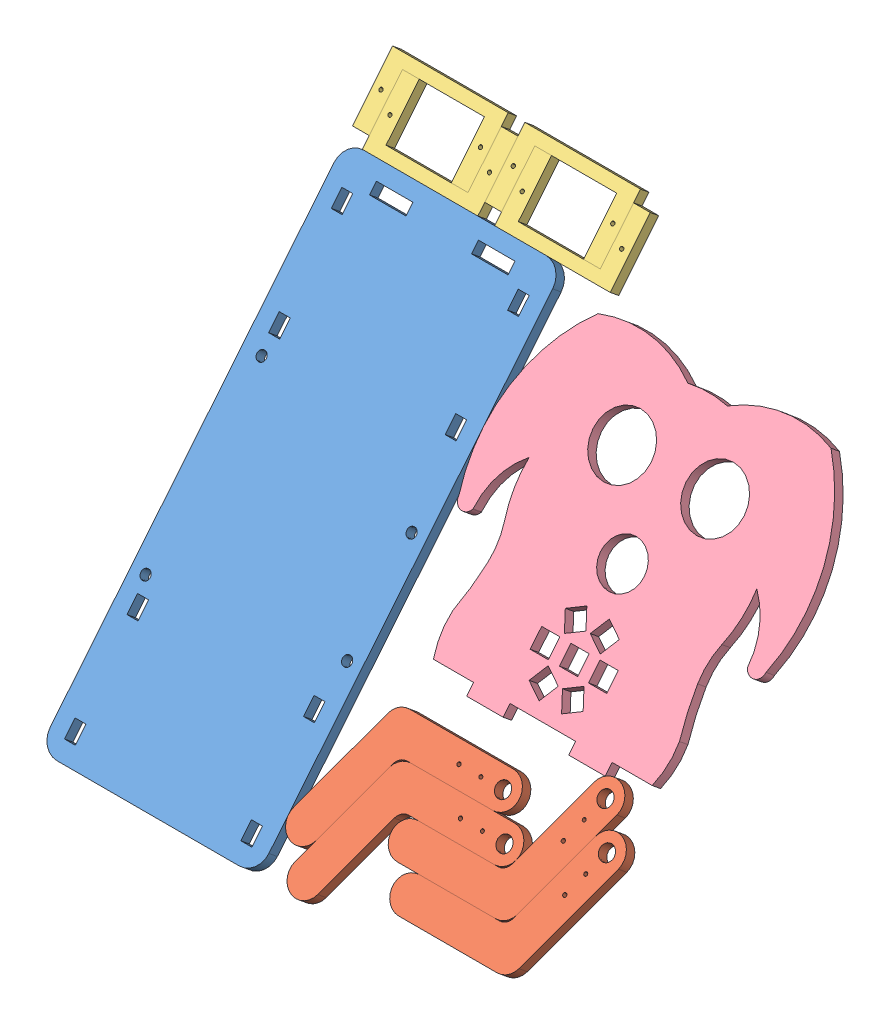
SolidWorks assembly nelo_laser_cutting, configuration Default. Lengths in mm.
Overall size (150 131.69 110.02).
10 component instances, 4 part files, 31 mates.
Components (placement in the parent):
- Base-1: Base [Default] at (2.0044 259.9739 585.3012) x (1 0 0) z (0 -0.774097 0.633066) size (60 3 133)
- leg-1: leg [Default] at (79.2182 266.4842 583.8525) x (0.369302 0.719376 -0.588315) z (-0.929309 0.285876 -0.233793) size (46.53 3 35.49)
- leg-2: leg [Default] at (117.2177 253.7498 590.3913) x (1 0 0) z (0 -0.774097 0.633066) size (46.53 3 35.49)
- leg-3: leg [Default] at (85.3263 259.5173 589.5501) x (0.369302 0.719376 -0.588315) z (-0.929309 0.285876 -0.233793) size (46.53 3 35.49)
- leg-4: leg [Default] at (111.1097 260.7167 584.6937) x (1 0 0) z (0 -0.774097 0.633066) size (46.53 3 35.49)
- servo_support-5: servo_support [Default] at (38.3044 357.0457 505.9147) x (-1 0 0) z (0 0.633066 0.774097) size (31.7 17.4 3)
- servo_support-6: servo_support [Default] at (2.0044 345.8987 515.0308) x (1 0 0) z (0 0.633066 0.774097) size (31.7 17.4 3)
- servo_support-7: servo_support [Default] at (38.3044 345.8987 515.0308) x (1 0 0) z (0 0.633066 0.774097) size (31.7 17.4 3)
- servo_support-8: servo_support [Default] at (42.9044 358.9449 508.237) x (1 0 0) z (0 -0.633066 -0.774097) size (31.7 17.4 3)
- dog_face-1: dog_face [Default] at (65.0617 342.7 517.6468) x (0 -0.774097 0.633066) z (0 0.633066 0.774097) size (79.03 88.48 3)
Mates (geometry in assembly coordinates):
- Coincident2: coincident: plane of Base-1 through (57.0044 246.3911 600.2848) normal (0 0.633066 0.774097); plane of leg-4 through (127.7168 278.9626 573.6475) normal (0 0.633066 0.774097)
- Coincident4: coincident: plane of leg-2 through (133.8248 271.9957 579.3451) normal (0 0.633066 0.774097); plane of leg-4 through (127.7168 278.9626 573.6475) normal (0 0.633066 0.774097)
- Coincident10: coincident: plane of leg-2 through (118.2097 254.9769 593.2633) normal (0 0.774097 -0.633066); plane of leg-4 through (90.1917 254.9769 593.2633) normal (0 -0.774097 0.633066)
- Coincident11: coincident: plane of leg-2 through (129.6429 273.2821 578.293) normal (-0.929309 0.285876 -0.233793); plane of leg-4 through (131.8987 277.6761 574.6996) normal (0.929309 -0.285876 0.233793)
- Coincident14: coincident: plane of leg-1 through (104.9755 267.0115 579.5458) normal (0 -0.774097 0.633066); plane of leg-3 through (111.0836 267.0115 579.5458) normal (0 0.774097 -0.633066)
- Coincident15: coincident: plane of leg-1 through (78.7776 265.5468 580.7436) normal (0.929309 -0.285876 0.233793); plane of leg-3 through (68.4305 245.3913 597.227) normal (-0.929309 0.285876 -0.233793)
- Coincident16: coincident: plane of leg-2 through (133.8248 270.0965 577.0228) normal (0 -0.633066 -0.774097); plane of leg-3 through (111.0836 263.528 582.3946) normal (0 -0.633066 -0.774097)
- Coincident17: coincident: plane of leg-1 through (104.9755 272.3941 579.0193) normal (0 0.633066 0.774097); plane of leg-3 through (111.0836 265.4272 584.7169) normal (0 0.633066 0.774097)
- Coincident18: coincident: plane of leg-3 through (111.0836 260.0446 585.2434) normal (0 -0.774097 0.633066); plane of leg-4 through (112.1016 261.9438 587.5657) normal (0 0.774097 -0.633066)
- Tangent1: tangent: cylinder of leg-3 through (111.0836 263.528 582.3946) axis (0 0.633066 0.774097) radius 4.5; plane of leg-4 through (123.5349 280.249 572.5954) normal (-0.929309 0.285876 -0.233793)
- Parallel1: parallel: plane of Base-1 through (7.0044 242.5206 603.4502) normal (0 -0.774097 0.633066); plane of leg-2 through (96.2997 248.01 598.9609) normal (0 -0.774097 0.633066)
- Tangent2: tangent: plane of Base-1 through (7.0044 242.5206 603.4502) normal (0 -0.774097 0.633066); cylinder of leg-3 through (72.6124 244.1049 598.2791) axis (0 0.633066 0.774097) radius 4.5
- Tangent3: tangent: plane of Base-1 through (62.0044 246.3911 600.2848) normal (1 0 0); cylinder of leg-1 through (66.5044 251.0717 592.5815) axis (0 0.633066 0.774097) radius 4.5
- Distance5: distance = 1 mm: plane of Base-1 through (2.0044 246.3911 600.2848) normal (-1 0 0); line of assembly
- Distance6: distance = 1 mm: plane of Base-1 through (7.0044 242.5206 603.4502) normal (0 -0.774097 0.633066); line of assembly
- Coincident35: coincident: plane of Base-1 through (57.0044 246.3911 600.2848) normal (0 0.633066 0.774097); plane of servo_support-5 through (38.3044 358.9449 508.237) normal (0 0.633066 0.774097)
- Coincident37: coincident: plane of servo_support-5 through (38.3044 358.9449 508.237) normal (0 0.633066 0.774097); plane of servo_support-6 through (2.0044 347.7979 517.3531) normal (0 0.633066 0.774097)
- Coincident38: coincident: plane of servo_support-5 through (33.7044 358.9449 508.237) normal (-1 0 0); plane of servo_support-6 through (33.7044 347.7979 517.3531) normal (1 0 0)
- Coincident39: coincident: plane of servo_support-5 through (33.7044 347.7979 517.3531) normal (0 0.774097 -0.633066); plane of servo_support-6 through (29.1044 347.7979 517.3531) normal (0 -0.774097 0.633066)
- Coincident40: coincident: plane of Base-1 through (7.0044 345.4756 519.2523) normal (0 0.774097 -0.633066); plane of servo_support-5 through (6.6044 345.4756 519.2523) normal (0 -0.774097 0.633066)
- Coincident41: coincident: plane of Base-1 through (2.0044 246.3911 600.2848) normal (-1 0 0); plane of servo_support-6 through (2.0044 361.2672 506.3378) normal (-1 0 0)
- Coincident42: coincident: plane of servo_support-5 through (38.3044 345.4756 519.2523) normal (1 0 0); plane of servo_support-7 through (38.3044 361.2672 506.3378) normal (-1 0 0)
- Coincident43: coincident: plane of Base-1 through (57.0044 246.3911 600.2848) normal (0 0.633066 0.774097); plane of servo_support-7 through (38.3044 347.7979 517.3531) normal (0 0.633066 0.774097)
- Coincident44: coincident: plane of servo_support-6 through (33.7044 361.2672 506.3378) normal (0 0.774097 -0.633066); plane of servo_support-7 through (70.0044 361.2672 506.3378) normal (0 0.774097 -0.633066)
- Coincident45: coincident: plane of Base-1 through (57.0044 246.3911 600.2848) normal (0 0.633066 0.774097); plane of servo_support-8 through (42.9044 358.9449 508.237) normal (0 0.633066 0.774097)
- Coincident47: coincident: plane of Base-1 through (7.0044 345.4756 519.2523) normal (0 0.774097 -0.633066); plane of servo_support-8 through (74.6044 343.5764 516.93) normal (0 -0.774097 0.633066)
- Coincident48: coincident: plane of servo_support-7 through (42.9044 347.7979 517.3531) normal (1 0 0); plane of servo_support-8 through (42.9044 343.5764 516.93) normal (-1 0 0)
- Coincident49: coincident: plane of Base-1 through (57.0044 246.3911 600.2848) normal (0 0.633066 0.774097); plane of dog_face-1 through (146.0329 308.1195 549.8026) normal (0 0.633066 0.774097)
- Parallel6: parallel: plane of Base-1 through (7.0044 242.5206 603.4502) normal (0 -0.774097 0.633066); plane of dog_face-1 through (87.243 282.446 570.7987) normal (0 -0.774097 0.633066)
- Tangent7: tangent: plane of Base-1 through (62.0044 246.3911 600.2848) normal (1 0 0); cylinder of dog_face-1 through (106.4027 318.6338 541.2038) axis (0 -0.633066 -0.774097) radius 44.3983
- Tangent8: tangent: cylinder of leg-4 through (127.7168 278.9626 573.6475) axis (0 -0.633066 -0.774097) radius 4.5; line of dog_face-1 through (125.243 281.8724 571.2678) axis (0 -0.633066 -0.774097)
